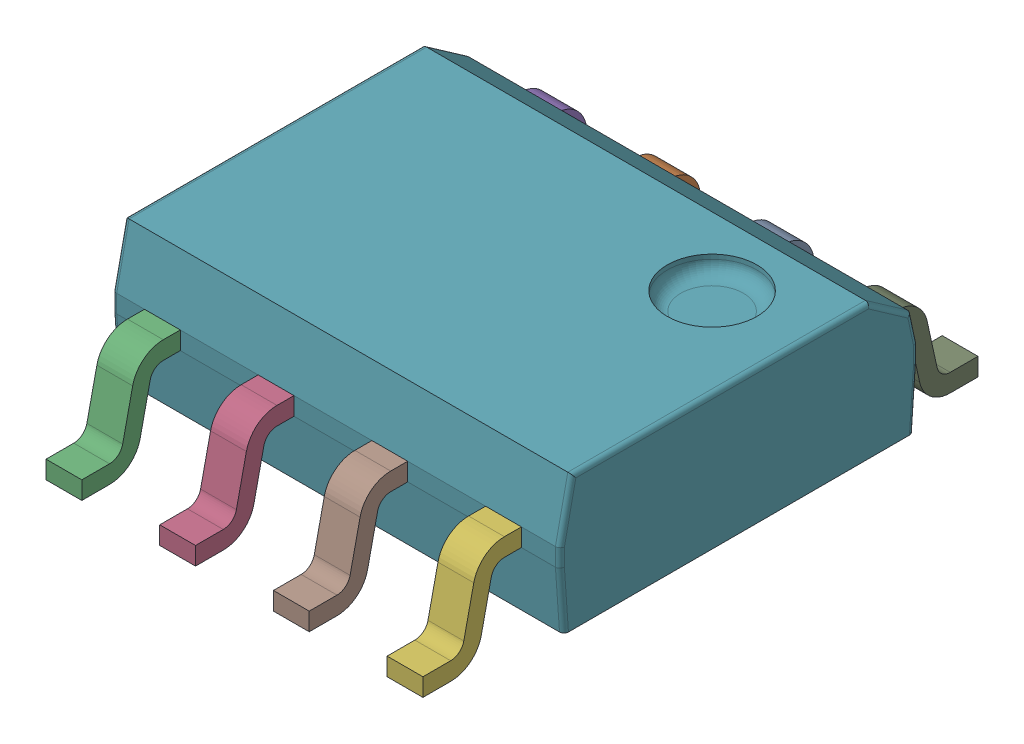
SolidWorks assembly User_Library-SOIC-8-150_1, configuration Default. Lengths in mm.
Overall size (5 1.75 6.2).
9 component instances, 2 part files, 0 mates.
Components (placement in the parent):
- User_Library-SOIC-8-150_pin_SOIC_SO-150_1-1: User_Library-SOIC-8-150_pin_SOIC_SO-150_1 [Default] at (0.6 0 -2) x (-1 0 0) z (0 0 -1) size (0.4 1.1 1.1)
- User_Library-SOIC-8-150_pin_SOIC_SO-150_1-2: User_Library-SOIC-8-150_pin_SOIC_SO-150_1 [Default] at (-0.67 0 -2) x (-1 0 0) z (0 0 -1) size (0.4 1.1 1.1)
- User_Library-SOIC-8-150_pin_SOIC_SO-150_1-3: User_Library-SOIC-8-150_pin_SOIC_SO-150_1 [Default] at (-1.94 0 2) size (0.4 1.1 1.1)
- User_Library-SOIC-8-150_pin_SOIC_SO-150_1-4: User_Library-SOIC-8-150_pin_SOIC_SO-150_1 [Default] at (-0.67 0 2) size (0.4 1.1 1.1)
- User_Library-SOIC-8-150_pin_SOIC_SO-150_1-5: User_Library-SOIC-8-150_pin_SOIC_SO-150_1 [Default] at (-1.94 0 -2) x (-1 0 0) z (0 0 -1) size (0.4 1.1 1.1)
- User_Library-SOIC-8-150_pin_SOIC_SO-150_1-6: User_Library-SOIC-8-150_pin_SOIC_SO-150_1 [Default] at (1.87 0 2) size (0.4 1.1 1.1)
- User_Library-SOIC-8-150_SOIC_150_SOIC_5X4_1-1: User_Library-SOIC-8-150_SOIC_150_SOIC_5X4_1 [Default] at origin size (5 1.5 4)
- User_Library-SOIC-8-150_pin_SOIC_SO-150_1-7: User_Library-SOIC-8-150_pin_SOIC_SO-150_1 [Default] at (0.6 0 2) size (0.4 1.1 1.1)
- User_Library-SOIC-8-150_pin_SOIC_SO-150_1-8: User_Library-SOIC-8-150_pin_SOIC_SO-150_1 [Default] at (1.87 0 -2) x (-1 0 0) z (0 0 -1) size (0.4 1.1 1.1)
